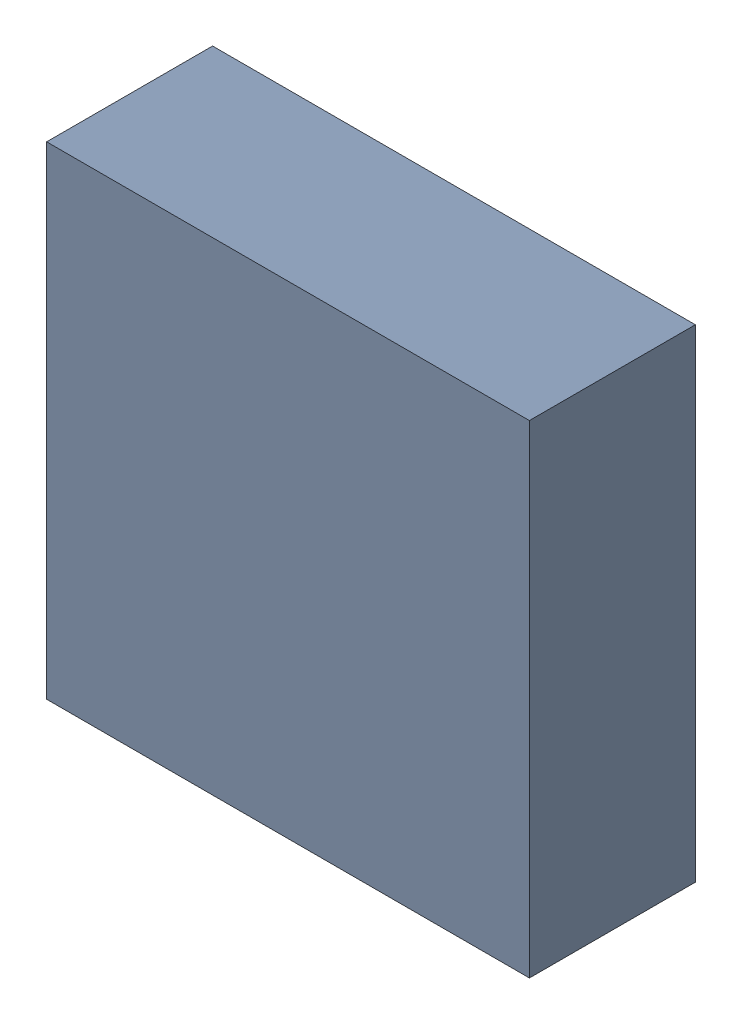
SolidWorks assembly U400PCB, configuration Default. Lengths in mm.
Overall size (3.2 3.2 1.1).
2 component instances, 1 part files, 0 mates.
Components (placement in the parent):
- 846484240-1: 846484240 [Default] at (127.4 102.9 0) size (3.2 3.2 1.1)
  - Extruded_11-1: Extruded_11 [Default] at origin size (3.2 3.2 1.1)
